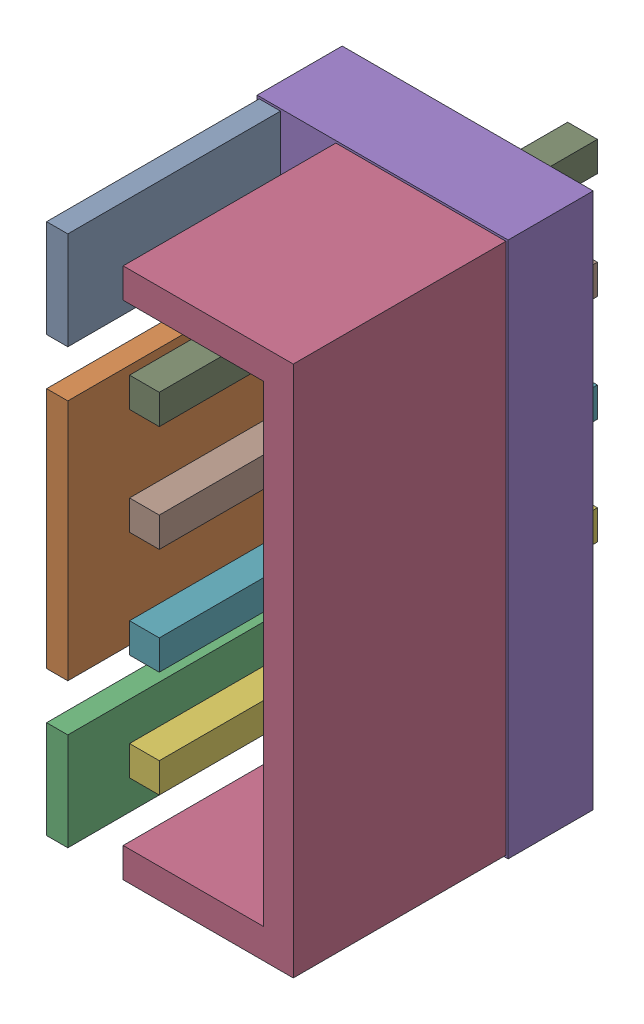
SolidWorks assembly X2, configuration По умолчанию. Lengths in mm.
Overall size (5.9 12.6 10.3).
18 component instances, 5 part files, 0 mates.
Components (placement in the parent):
- 368956736-1: 368956736 [По умолчанию] at (38.45 17.6 0.0127) size (0.5 2.3 7)
  - Extruded-1: Extruded [По умолчанию] at origin size (0.5 2.3 7)
- 368956992-1: 368956992 [По умолчанию] at (38.45 12.5 0.0127) size (0.5 5.7 7)
  - Extruded_1-1: Extruded_1 [По умолчанию] at origin size (0.5 5.7 7)
- 368956736-2: 368956736 [По умолчанию] at (38.45 7.4 0.0127) size (0.5 2.3 7)
  - Extruded-1: Extruded [По умолчанию] at origin size (0.5 2.3 7)
- 368957248-1: 368957248 [По умолчанию] at (42 12.5 0.0127) size (4 12.5 7)
  - Extruded_2-1: Extruded_2 [По умолчанию] at origin size (4 12.5 7)
- 368957376-1: 368957376 [По умолчанию] at (41.1 12.5 0.0127) size (5.9 12.6 2)
  - Extruded_3-1: Extruded_3 [По умолчанию] at origin size (5.9 12.6 2)
- 368955840-1: 368955840 [По умолчанию] at (40.5 8.75 -3.2873) size (0.7 0.7 10.3)
  - Extruded_4-1: Extruded_4 [По умолчанию] at origin size (0.7 0.7 10.3)
- 368955840-2: 368955840 [По умолчанию] at (40.5 11.25 -3.2873) size (0.7 0.7 10.3)
  - Extruded_4-1: Extruded_4 [По умолчанию] at origin size (0.7 0.7 10.3)
- 368955840-3: 368955840 [По умолчанию] at (40.5 13.75 -3.2873) size (0.7 0.7 10.3)
  - Extruded_4-1: Extruded_4 [По умолчанию] at origin size (0.7 0.7 10.3)
- 368955840-4: 368955840 [По умолчанию] at (40.5 16.25 -3.2873) size (0.7 0.7 10.3)
  - Extruded_4-1: Extruded_4 [По умолчанию] at origin size (0.7 0.7 10.3)
